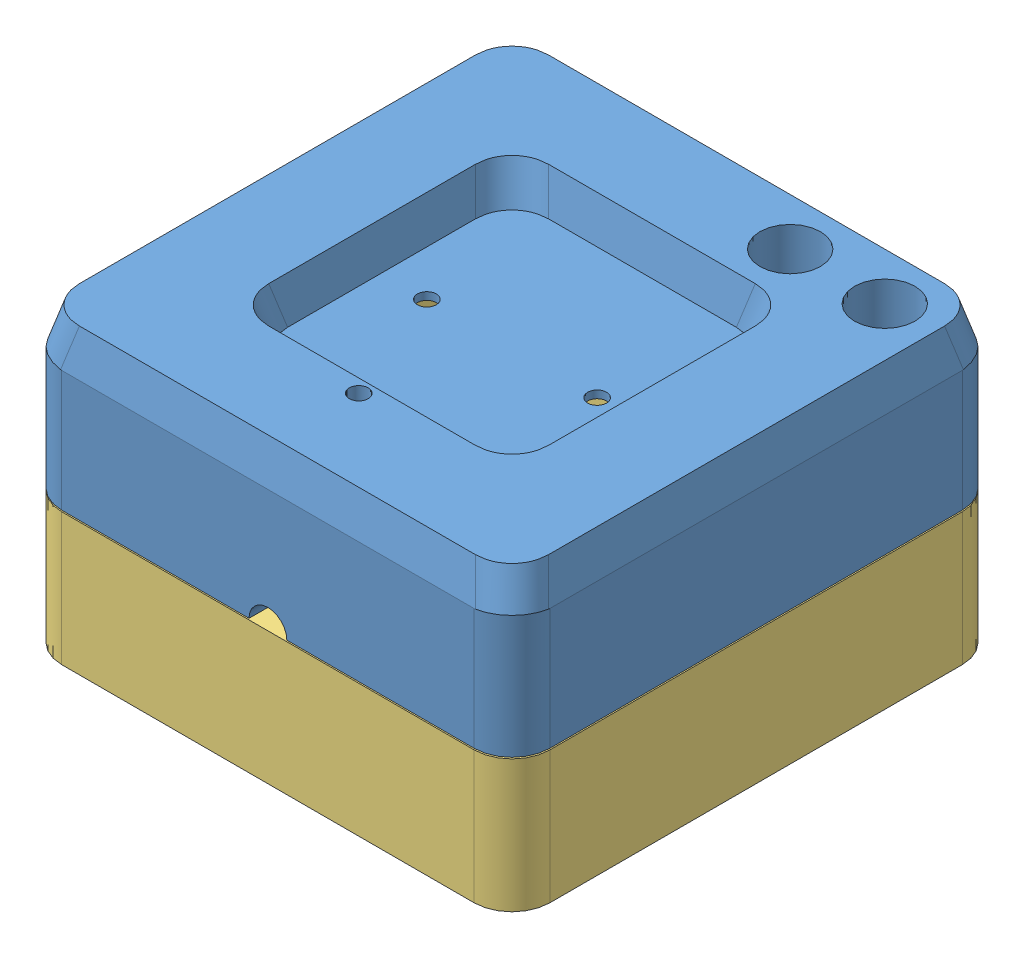
SolidWorks assembly Assembled, configuration Default. Lengths in mm.
Overall size (129 77.36 139).
3 component instances, 3 part files, 6 mates.
Components (placement in the parent):
- Base Mount-1: Base Mount [Default] at origin size (129 42 129)
- Slider Knob-2: Slider Knob [Default] at (-29.5 -20 -64.5) x (-1 0 0) z (0 0 -1) size (20 10 25)
- Mating Base-1: Mating Base [Default] at (0 -32.3579 0) size (129 40 129)
Mates (geometry in assembly coordinates):
- Coincident2: coincident anti-aligned: plane of Base Mount-1 through (-64.5 -2 -64.5) normal (0 0 -1); plane of Slider Knob-2 through (-29.5 -20 -64.5) normal (0 0 1)
- Coincident3: coincident anti-aligned: plane of Base Mount-1 through (39.5 -22 19.6581) normal (0 1 0); plane of Slider Knob-2 through (-39.5 -22 -49.5) normal (0 -1 0)
- LimitDistance1: limit distance = 59 mm anti-aligned: plane of Base Mount-1 through (39.5 -22 19.6581) normal (-1 0 0); plane of Slider Knob-2 through (-19.5 -25 -74.5) normal (1 0 0)
- LimitDistance2: limit distance = 0 mm anti-aligned: plane of Base Mount-1 through (-39.5 -22 19.6581) normal (1 0 0); plane of Slider Knob-2 through (-39.5 -25 -74.5) normal (-1 0 0)
- Width2: width anti-aligned: plane of Base Mount-1 through (59.5 -32 -64.5) normal (-1 0 0); plane of Base Mount-1 through (-59.5 -32 64.5) normal (1 0 0); plane of Mating Base-1 through (-54.5 -221.5071 -54.5) normal (1 0 0); plane of Mating Base-1 through (54.5 -221.5071 54.5) normal (-1 0 0)
- Width3: width anti-aligned: plane of Base Mount-1 through (64.5 -32 59.5) normal (0 0 -1); plane of Base Mount-1 through (-64.5 -32 -59.5) normal (0 0 1); plane of Mating Base-1 through (-57.5 -27.3579 57.5) normal (0 0 1); plane of Mating Base-1 through (-57.5 -27.3579 -57.5) normal (0 0 -1)
